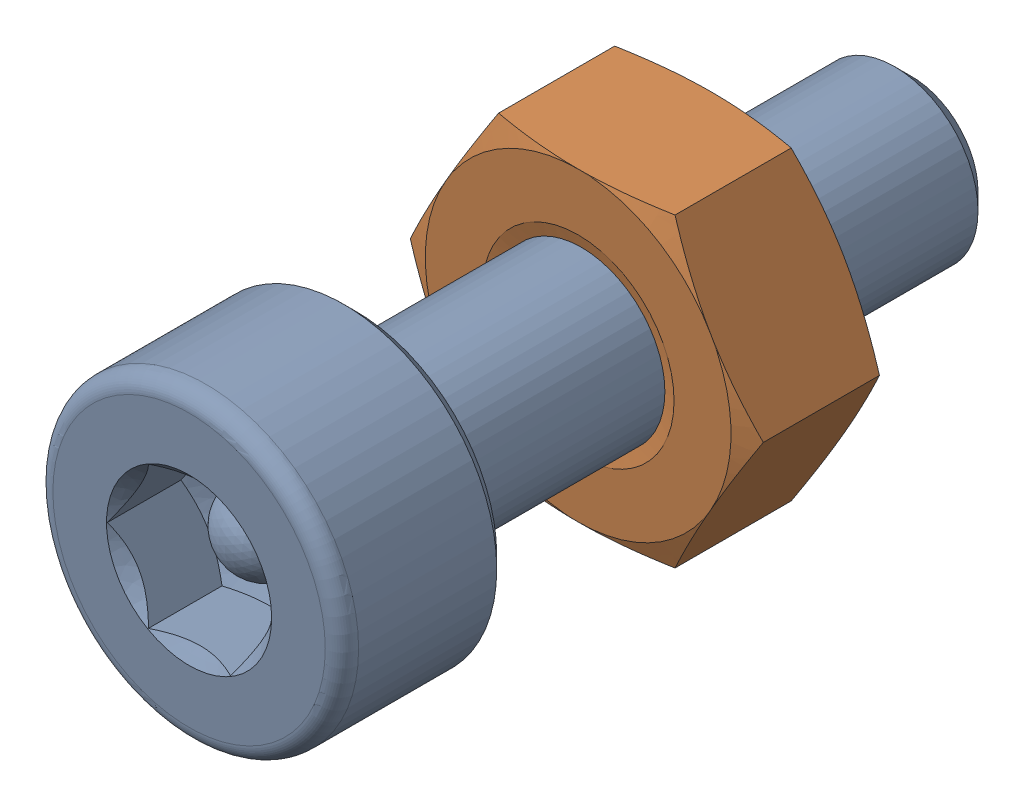
SolidWorks assembly Screw and Nut M3x010_012, configuration Varsayılan. Lengths in mm.
Overall size (6.35 5.5 13.14).
2 component instances, 2 part files, 0 mates.
Components (placement in the parent):
- M3x10-Screw011-1: M3x10-Screw011 [Varsayılan] at origin size (5.5 5.5 13.14)
- M3-Nut043-1: M3-Nut043 [Varsayılan] at (0 0 -4) x (-1 0 0) z (0 0 -1) size (6.35 5.5 2.4)
